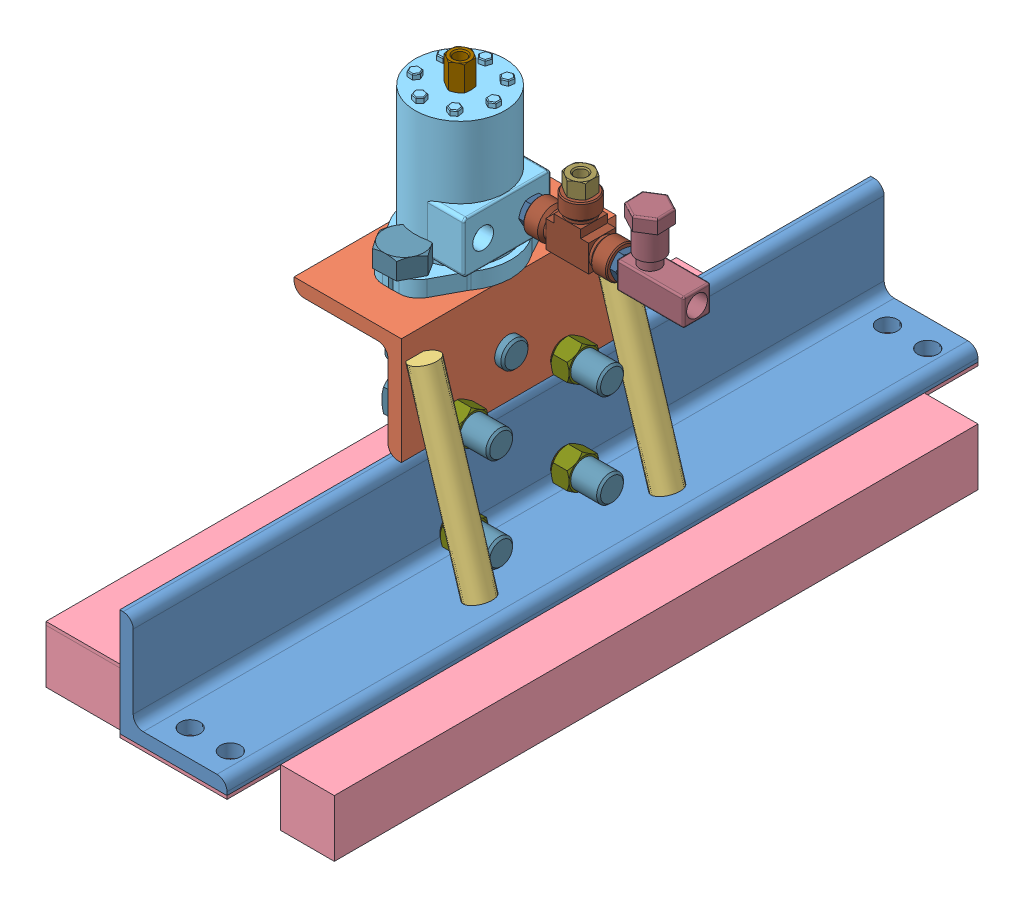
SolidWorks assembly 01-076-00-0, configuration Default. Lengths in mm.
Overall size (295.22 416.18 711.2).
44 component instances, 19 part files, 78 mates.
Components (placement in the parent):
- 01-048-00-0-1: 01-048-00-0 [Default] at (-161.4838 -113.0009 54.5674) size (279.4 257.18 711.2)
  - 01-042-00-0-1: 01-042-00-0 [Default] at origin size (101.6 101.6 711.2)
  - 01-043-00-0-1: 01-043-00-0 [Default] at (12.7 203.2 0) x (-1 0 0) z (0 0 1) size (101.6 101.6 203.2)
  - 01-047-00-0-5: 01-047-00-0 [Default] at (74.1068 15.97 -88.9) x (0.948496 0.291905 -0.123074) z (0.11763 0.036201 0.992397) size (25.4 177.8 25.4)
  - 01-047-00-0-7: 01-047-00-0 [Default] at (74.1066 15.5263 89.0193) x (0.948496 0.291905 -0.123074) z (0.11763 0.036201 0.992397) size (25.4 177.8 25.4)
  - 01-074-00-0-1: 01-074-00-0 [Default] at (0 -3.175 298.45) x (0 0 -1) z (1 0 0) size (711.2 53.98 279.4)
- BMPH50H2KP-1: BMPH50H2KP [Default] at (-194.7832 90.1991 54.5674) x (0 0 -1) z (-1 0 0) size (131.32 192.98 96.77)
- 01-077-00-0-1: 01-077-00-0 [Default] at (-220.4962 -153.8949 79.6504) x (0.999923 0 0.012402) z (-0.012402 0 0.999923) size (177.8 190.5 152.4)
  - 01-044-00-0-1: 01-044-00-0 [Default] at origin size (127 25.4 50.8)
  - 01-045-00-0-1: 01-045-00-0 [Default] at (177.8 0 50.8) x (0 0 -1) z (1 0 0) size (152.4 25.4 50.8)
  - 01-046-00-0-1: 01-046-00-0 [Default] at (25.4 6.35 -25.4) size (25.4 184.15 25.4)
- SS-4-SAE-7_4-1: SS-4-SAE-7_4 [Default] at (-194.7832 215.6751 54.5674) x (0 1 0) z (0 0 1) size (33.53 19.05 22)
- Male Hex Nipple, NPT_SS-8-HN_1_2-1: Male Hex Nipple, NPT_SS-8-HN_1_2 [Default] at (-123.1933 132.8711 31.7074) x (-1 0 0) z (0 0 -1) size (46.74 22.23 25.66)
- SS-8-T_3-1: SS-8-T_3 [Default] at (-63.7954 132.8711 31.7074) x (-1 0 0) z (0 -1 0) size (79.25 30.48 54.86)
- SS-8-RB-4-1: SS-8-RB-4 [Default] at (-103.4194 159.7951 31.7074) x (0 1 0) z (0 0 1) size (27.43 22.23 25.66)
- Male Hex Nipple, NPT_SS-8-HN_1_2-2: Male Hex Nipple, NPT_SS-8-HN_1_2 [Default] at (-36.9095 132.8711 31.7074) x (-1 0 0) z (0 -0.924225 -0.381849) size (46.74 22.23 25.66)
- Control Valve - 0.5NPTF-1: Control Valve - 0.5NPTF [Default] at (6.7404 120.1711 19.0074) x (0 0 1) z (-1 0 0) size (34.87 73.03 63.5)
- hex bolt_ai_2-1: hex bolt_ai_2 [PreviewCfg] at (-194.7832 123.2191 107.7804) x (0 -1 0) z (0.883967 0 0.467549) size (93.98 43.99 38.1)
- flat washer type a wide_ai-1: flat washer type a wide_ai [PreviewCfg] at (-194.7832 77.4991 107.7804) x (0 1 0) z (0 0 1) size (4.19 63.5 63.5)
- hex nut_ai-1: hex nut_ai [PreviewCfg] at (-194.7832 56.4171 107.7804) x (0.996756 0 0.080478) z (0 -1 0) size (28.57 33 16.89)
- hex bolt_ai_2-2: hex bolt_ai_2 [PreviewCfg] at (-194.7832 123.2191 1.3544) x (0 -1 0) z (0.883967 0 0.467549) size (93.98 43.99 38.1)
- flat washer type a wide_ai-2: flat washer type a wide_ai [PreviewCfg] at (-194.7832 77.4991 1.3544) x (0 1 0) z (0 0 1) size (4.19 63.5 63.5)
- hex nut_ai-2: hex nut_ai [PreviewCfg] at (-194.7832 56.4171 1.3544) x (0.996756 0 0.080478) z (0 -1 0) size (28.57 33 16.89)
- 01-078-00-0-1: 01-078-00-0 [Default] at (-161.4838 -68.6017 124.5698) x (0 0 -1) z (0 1 0) size (140 67.2 38)
- 01-078-00-0-2: 01-078-00-0 [Default] at (-161.4838 20.2983 124.5698) x (0 0 -1) z (0 1 0) size (140 67.2 38)
- WASHER 0.375-WIDE-1: WASHER 0.375-WIDE [Default] at (-177.4858 -87.6009 107.0565) size (2.11 25.4 25.4)
- hex bolt_ai_2-3: hex bolt_ai_2 [PreviewCfg] at (-197.374 -87.6009 107.0565) size (93.98 43.99 38.1)
- WASHER 0.375-WIDE-2: WASHER 0.375-WIDE [Default] at (-146.6756 -87.6009 107.0565) size (2.11 25.4 25.4)
- hex nut_ai-3: hex nut_ai [PreviewCfg] at (-146.6756 -87.6009 107.0565) x (0 0 1) z (-1 0 0) size (28.57 33 16.89)
- hex bolt_ai_2-4: hex bolt_ai_2 [PreviewCfg] at (-197.374 -87.6009 2.0783) size (93.98 43.99 38.1)
- WASHER 0.375-WIDE-3: WASHER 0.375-WIDE [Default] at (-146.6756 -87.6009 2.0783) size (2.11 25.4 25.4)
- hex nut_ai-4: hex nut_ai [PreviewCfg] at (-146.6756 -87.6009 2.0783) x (0 0 1) z (-1 0 0) size (28.57 33 16.89)
- WASHER 0.375-WIDE-4: WASHER 0.375-WIDE [Default] at (-177.4858 -87.6009 2.0783) size (2.11 25.4 25.4)
- hex bolt_ai_2-5: hex bolt_ai_2 [PreviewCfg] at (-197.374 1.2991 107.0565) size (93.98 43.99 38.1)
- WASHER 0.375-WIDE-5: WASHER 0.375-WIDE [Default] at (-146.6756 1.2991 107.0565) size (2.11 25.4 25.4)
- hex nut_ai-5: hex nut_ai [PreviewCfg] at (-146.6756 1.2991 107.0565) x (0 0 1) z (-1 0 0) size (28.57 33 16.89)
- WASHER 0.375-WIDE-6: WASHER 0.375-WIDE [Default] at (-177.4858 1.2991 107.0565) size (2.11 25.4 25.4)
- hex bolt_ai_2-6: hex bolt_ai_2 [PreviewCfg] at (-197.374 1.2991 2.0783) size (93.98 43.99 38.1)
- WASHER 0.375-WIDE-7: WASHER 0.375-WIDE [Default] at (-146.6756 1.2991 2.0783) size (2.11 25.4 25.4)
- hex nut_ai-6: hex nut_ai [PreviewCfg] at (-146.6756 1.2991 2.0783) x (0 0 1) z (-1 0 0) size (28.57 33 16.89)
- WASHER 0.375-WIDE-8: WASHER 0.375-WIDE [Default] at (-177.4858 1.2991 2.0783) size (2.11 25.4 25.4)
- 01-085-00-0-1: 01-085-00-0 [Default] at (-194.7832 20.7301 54.5674) x (-0.012402 0 0.999923) z (-0.999923 0 -0.012402) size (44.45 50.8 44.45)
- hex bolt_ai_2-7: hex bolt_ai_2 [PreviewCfg] at (-234.7851 30.2551 54.0712) x (0.999923 0 0.012402) z (0.002836 0.973504 -0.228653) size (93.98 43.99 38.1)
- hex nut_ai-7: hex nut_ai [PreviewCfg] at (-172.5599 30.2551 54.843) x (-0.012135 0.206523 0.978366) z (-0.999923 0 -0.012402) size (28.57 33 16.89)
Mates (geometry in assembly coordinates):
- Coincident3: coincident anti-aligned: plane of 01-048-00-0-1/01-043-00-0-1 through (-250.3838 90.1991 156.1674) normal (0 1 0); plane of BMPH50H2KP-1 through (-194.7832 90.1991 54.5674) normal (0 -1 0)
- Concentric3: concentric anti-aligned: cylinder of BMPH50H2KP-1 through (-194.7832 105.4391 1.3544) axis (0 -1 0) radius 6.731; cylinder of 01-048-00-0-1/01-043-00-0-1 through (-194.7832 211.4325 1.3544) axis (0 1 0) radius 7.9375
- Concentric5: concentric anti-aligned: cylinder of BMPH50H2KP-1 through (-194.7832 36.6051 54.5674) axis (0 1 0) radius 12.7; cylinder of 01-077-00-0-1/01-044-00-0-1 through (-194.7832 -128.4939 54.5674) axis (0 -1 0) radius 12.7
- Concentric7: concentric anti-aligned: cylinder of BMPH50H2KP-1 through (-194.7832 36.6051 54.5674) axis (0 1 0) radius 12.7; cylinder of 01-077-00-0-1/01-046-00-0-1 through (-194.7832 36.6051 54.5674) axis (0 -1 0) radius 12.7
- Concentric8: concentric aligned: cylinder of SS-4-SAE-7_4-1 through (-194.7832 219.1168 54.5674) axis (0 1 0) radius 5.5563; cylinder of BMPH50H2KP-1 through (-194.7832 224.8191 54.5674) axis (0 1 0) radius 4.9606
- Coincident4: coincident anti-aligned: plane of BMPH50H2KP-1 through (-194.7832 224.8191 54.5674) normal (0 1 0); plane of SS-4-SAE-7_4-1 through (-194.7832 224.8191 59.3299) normal (0 -1 0)
- Coincident5: coincident anti-aligned: plane of BMPH50H2KP-1 through (-150.0792 108.6141 13.2924) normal (1 0 0); circle of Male Hex Nipple, NPT_SS-8-HN_1_2-1
- Concentric10: concentric aligned: cone of BMPH50H2KP-1 through (-150.0792 132.8711 31.7074) axis (-1 0 0); cone of Male Hex Nipple, NPT_SS-8-HN_1_2-1 through (-156.3733 132.8711 31.7074) axis (-1 0 0)
- Coincident6: coincident aligned: circle of Male Hex Nipple, NPT_SS-8-HN_1_2-1; plane of SS-8-T_3-1 through (-143.0434 132.8711 31.7074) normal (-1 0 0)
- Concentric11: concentric anti-aligned: cylinder of Male Hex Nipple, NPT_SS-8-HN_1_2-1 through (-136.7493 132.8711 31.7074) axis (-1 0 0) radius 10.668; cylinder of SS-8-T_3-1 through (-143.0434 132.8711 31.7074) axis (1 0 0) radius 15.24
- Parallel1: parallel anti-aligned: plane of SS-8-T_3-1 through (-123.7394 120.1711 19.0074) normal (0 0 -1); plane of assembly through (0 0 0) normal (0 0 1)
- Concentric12: concentric aligned: cone of SS-8-T_3-1 through (-103.4194 158.9239 31.7074) axis (0 -1 0); cone of SS-8-RB-4-1 through (-103.4194 172.4951 31.7074) axis (0 -1 0)
- Coincident8: coincident anti-aligned: plane of SS-8-T_3-1 through (-103.4194 172.4951 31.7074) normal (0 1 0); circle of SS-8-RB-4-1
- Concentric13: concentric aligned: cone of SS-8-T_3-1 through (-77.3666 132.8711 31.7074) axis (-1 0 0); cone of Male Hex Nipple, NPT_SS-8-HN_1_2-2 through (-70.0895 132.8711 31.7074) axis (-1 0 0)
- Coincident9: coincident anti-aligned: plane of SS-8-T_3-1 through (-63.7954 132.8711 31.7074) normal (1 0 0); circle of Male Hex Nipple, NPT_SS-8-HN_1_2-2
- Concentric14: concentric aligned: cone of Male Hex Nipple, NPT_SS-8-HN_1_2-2 through (-50.4655 132.8711 31.7074) axis (1 0 0); cone of Control Valve - 0.5NPTF-1 through (-56.7596 132.8711 31.7074) axis (1 0 0)
- Coincident10: coincident aligned: circle of Male Hex Nipple, NPT_SS-8-HN_1_2-2; plane of Control Valve - 0.5NPTF-1 through (-56.7596 145.5711 19.0074) normal (-1 0 0)
- Concentric15: concentric anti-aligned: cylinder of 01-048-00-0-1/01-043-00-0-1 through (-194.7832 211.4325 107.7804) axis (0 1 0) radius 7.9375; cylinder of BMPH50H2KP-1 through (-194.7832 105.4391 107.7804) axis (0 -1 0) radius 6.731
- Coincident12: coincident aligned: plane of SS-8-T_3-1 through (-123.7394 120.1711 19.0074) normal (0 0 -1); plane of Control Valve - 0.5NPTF-1 through (-56.7596 120.1711 19.0074) normal (0 0 -1)
- Coincident13: coincident anti-aligned: plane of BMPH50H2KP-1 through (-194.7832 105.4391 54.5674) normal (0 1 0); plane of hex bolt_ai_2-1 through (-184.4985 105.4391 88.3357) normal (0 -1 0)
- Concentric16: concentric anti-aligned: cylinder of BMPH50H2KP-1 through (-194.7832 105.4391 107.7804) axis (0 -1 0) radius 6.731; cylinder of hex bolt_ai_2-1 through (-194.7832 123.2191 107.7804) axis (0 1 0) radius 12.7
- Concentric171: concentric anti-aligned: cylinder of hex bolt_ai_2-1 through (-194.7832 123.2191 107.7804) axis (0 1 0) radius 12.7; cylinder of hex nut_ai-1 through (-194.7832 81.4546 107.7804) axis (0 -1 0) radius 9.525
- Coincident141: coincident anti-aligned: plane of flat washer type a wide_ai-1 through (-226.5332 73.3081 107.7804) normal (0 -1 0); plane of hex nut_ai-1 through (-196.1109 73.3081 124.2246) normal (0 1 0)
- Coincident15: coincident anti-aligned: plane of 01-048-00-0-1/01-043-00-0-1 through (-171.0088 77.4991 156.1674) normal (0 -1 0); plane of flat washer type a wide_ai-1 through (-208.2706 77.4991 107.7804) normal (0 1 0)
- Concentric18: concentric anti-aligned: cylinder of hex bolt_ai_2-2 through (-194.7832 123.2191 1.3544) axis (0 1 0) radius 12.7; cylinder of hex nut_ai-2 through (-194.7832 81.4546 1.3544) axis (0 -1 0) radius 9.525
- Coincident16: coincident anti-aligned: plane of flat washer type a wide_ai-2 through (-226.5332 73.3081 1.3544) normal (0 -1 0); plane of hex nut_ai-2 through (-196.1109 73.3081 17.7986) normal (0 1 0)
- Coincident17: coincident anti-aligned: plane of BMPH50H2KP-1 through (-194.7832 105.4391 54.5674) normal (0 1 0); plane of hex bolt_ai_2-2 through (-184.4985 105.4391 -18.0903) normal (0 -1 0)
- Concentric19: concentric anti-aligned: cylinder of BMPH50H2KP-1 through (-194.7832 105.4391 1.3544) axis (0 -1 0) radius 6.731; cylinder of hex bolt_ai_2-2 through (-194.7832 123.2191 1.3544) axis (0 1 0) radius 12.7
- Coincident18: coincident anti-aligned: plane of 01-048-00-0-1/01-043-00-0-1 through (-171.0088 77.4991 156.1674) normal (0 -1 0); plane of flat washer type a wide_ai-2 through (-208.2706 77.4991 1.3544) normal (0 1 0)
- Concentric20: concentric aligned: circle of 01-048-00-0-1/01-043-00-0-1; cylinder of flat washer type a wide_ai-2 through (-194.7832 42.5741 1.3544) axis (0 -1 0) radius 13.4874
- Coincident19: coincident anti-aligned: plane of 01-048-00-0-1/01-042-00-0-1 through (-161.4838 -113.0009 410.1674) normal (-1 0 0); plane of 01-078-00-0-1 through (-161.4838 -106.6001 124.5698) normal (1 0 0)
- Perpendicular1: perpendicular: plane of 01-078-00-0-1 through (-177.4858 -106.6001 124.5698) normal (0 -1 0); plane of assembly through (0 0 54.5674) normal (0 0 1)
- Coincident22: coincident: moEndPointRef_w of 01-078-00-0-1; plane of assembly
- Distance4: distance = 25.4 mm anti-aligned: moEndPointRef_w of 01-078-00-0-1; plane of 01-048-00-0-1/01-042-00-0-1 through (-59.8838 -113.0009 410.1674) normal (0 -1 0)
- Coincident23: coincident anti-aligned: plane of 01-048-00-0-1/01-043-00-0-1 through (-161.4838 -1.881 156.1674) normal (-1 0 0); plane of 01-078-00-0-2 through (-161.4838 -17.7001 124.5698) normal (1 0 0)
- Perpendicular2: perpendicular: plane of 01-078-00-0-2 through (-177.4858 -17.7001 124.5698) normal (0 -1 0); plane of assembly through (0 0 54.5674) normal (0 0 1)
- Coincident24: coincident: moEndPointRef_w of 01-078-00-0-2; plane of assembly
- Distance5: distance = 12.7 mm anti-aligned: moEndPointRef_w of 01-078-00-0-2; plane of 01-048-00-0-1/01-043-00-0-1 through (-148.7838 -11.4009 156.1674) normal (0 -1 0)
- Coincident25: coincident anti-aligned: plane of 01-078-00-0-1 through (-177.4858 -106.6001 124.5698) normal (-1 0 0); plane of WASHER 0.375-WIDE-1 through (-177.4858 -82.0383 107.0565) normal (1 0 0)
- Concentric22: concentric aligned: cylinder of 01-048-00-0-1/01-042-00-0-1 through (-59.8828 -87.6009 107.0565) axis (-1 0 0) radius 6.35; cylinder of WASHER 0.375-WIDE-1 through (-212.4108 -87.6009 107.0565) axis (-1 0 0) radius 5.5626
- Concentric231: concentric aligned: cylinder of WASHER 0.375-WIDE-1 through (-212.4108 -87.6009 107.0565) axis (-1 0 0) radius 12.7; cylinder of hex bolt_ai_2-3 through (-197.374 -87.6009 107.0565) axis (-1 0 0) radius 12.7
- Coincident261: coincident anti-aligned: plane of WASHER 0.375-WIDE-1 through (-179.594 -74.9009 107.0565) normal (-1 0 0); plane of hex bolt_ai_2-3 through (-179.594 -65.6039 107.0565) normal (1 0 0)
- Coincident27: coincident anti-aligned: plane of 01-048-00-0-1/01-042-00-0-1 through (-148.7838 -20.9208 410.1674) normal (1 0 0); plane of WASHER 0.375-WIDE-2 through (-148.7838 -74.9009 107.0565) normal (-1 0 0)
- Concentric24: concentric aligned: cylinder of hex bolt_ai_2-3 through (-197.374 -87.6009 107.0565) axis (-1 0 0) radius 12.7; cylinder of WASHER 0.375-WIDE-2 through (-181.6006 -87.6009 107.0565) axis (-1 0 0) radius 5.5626
- Coincident28: coincident anti-aligned: plane of WASHER 0.375-WIDE-2 through (-146.6756 -82.0383 107.0565) normal (1 0 0); plane of hex nut_ai-3 through (-146.6756 -71.1031 107.0565) normal (-1 0 0)
- Concentric25: concentric aligned: cylinder of WASHER 0.375-WIDE-2 through (-181.6006 -87.6009 107.0565) axis (-1 0 0) radius 12.7; cylinder of hex nut_ai-3 through (-129.7846 -87.6009 107.0565) axis (-1 0 0) radius 8.3337
- Concentric26: concentric aligned: cylinder of hex bolt_ai_2-4 through (-197.374 -87.6009 2.0783) axis (-1 0 0) radius 12.7; cylinder of WASHER 0.375-WIDE-4 through (-212.4108 -87.6009 2.0783) axis (-1 0 0) radius 12.7
- Coincident29: coincident anti-aligned: plane of hex bolt_ai_2-4 through (-179.594 -65.6039 2.0783) normal (1 0 0); plane of WASHER 0.375-WIDE-4 through (-179.594 -74.9009 2.0783) normal (-1 0 0)
- Concentric27: concentric aligned: cylinder of hex bolt_ai_2-4 through (-197.374 -87.6009 2.0783) axis (-1 0 0) radius 12.7; cylinder of WASHER 0.375-WIDE-3 through (-181.6006 -87.6009 2.0783) axis (-1 0 0) radius 5.5626
- Coincident30: coincident anti-aligned: plane of WASHER 0.375-WIDE-3 through (-146.6756 -82.0383 2.0783) normal (1 0 0); plane of hex nut_ai-4 through (-146.6756 -71.1031 2.0783) normal (-1 0 0)
- Concentric28: concentric aligned: cylinder of WASHER 0.375-WIDE-3 through (-181.6006 -87.6009 2.0783) axis (-1 0 0) radius 12.7; cylinder of hex nut_ai-4 through (-129.7846 -87.6009 2.0783) axis (-1 0 0) radius 8.3337
- Coincident31: coincident anti-aligned: plane of 01-078-00-0-1 through (-177.4858 -106.6001 124.5698) normal (-1 0 0); plane of WASHER 0.375-WIDE-4 through (-177.4858 -82.0383 2.0783) normal (1 0 0)
- Concentric29: concentric aligned: cylinder of 01-048-00-0-1/01-042-00-0-1 through (-59.8828 -87.6009 2.0783) axis (-1 0 0) radius 6.35; cylinder of WASHER 0.375-WIDE-4 through (-212.4108 -87.6009 2.0783) axis (-1 0 0) radius 5.5626
- Coincident32: coincident anti-aligned: plane of 01-048-00-0-1/01-042-00-0-1 through (-148.7838 -20.9208 410.1674) normal (1 0 0); plane of WASHER 0.375-WIDE-3 through (-148.7838 -74.9009 2.0783) normal (-1 0 0)
- Concentric30: concentric aligned: cylinder of hex bolt_ai_2-5 through (-197.374 1.2991 107.0565) axis (-1 0 0) radius 12.7; cylinder of WASHER 0.375-WIDE-6 through (-212.4108 1.2991 107.0565) axis (-1 0 0) radius 12.7
- Coincident33: coincident anti-aligned: plane of hex bolt_ai_2-5 through (-179.594 23.2961 107.0565) normal (1 0 0); plane of WASHER 0.375-WIDE-6 through (-179.594 13.9991 107.0565) normal (-1 0 0)
- Concentric31: concentric aligned: cylinder of hex bolt_ai_2-5 through (-197.374 1.2991 107.0565) axis (-1 0 0) radius 12.7; cylinder of WASHER 0.375-WIDE-5 through (-181.6006 1.2991 107.0565) axis (-1 0 0) radius 5.5626
- Coincident34: coincident anti-aligned: plane of WASHER 0.375-WIDE-5 through (-146.6756 6.8617 107.0565) normal (1 0 0); plane of hex nut_ai-5 through (-146.6756 17.7969 107.0565) normal (-1 0 0)
- Concentric32: concentric aligned: cylinder of WASHER 0.375-WIDE-5 through (-181.6006 1.2991 107.0565) axis (-1 0 0) radius 12.7; cylinder of hex nut_ai-5 through (-129.7846 1.2991 107.0565) axis (-1 0 0) radius 8.3337
- Coincident35: coincident anti-aligned: plane of 01-078-00-0-2 through (-177.4858 -17.7001 124.5698) normal (-1 0 0); plane of WASHER 0.375-WIDE-6 through (-177.4858 6.8617 107.0565) normal (1 0 0)
- Coincident36: coincident anti-aligned: plane of 01-048-00-0-1/01-042-00-0-1 through (-148.7838 -20.9208 410.1674) normal (1 0 0); plane of WASHER 0.375-WIDE-5 through (-148.7838 13.9991 107.0565) normal (-1 0 0)
- Concentric33: concentric aligned: cylinder of 01-048-00-0-1/01-043-00-0-1 through (-148.7828 1.2991 107.0565) axis (-1 0 0) radius 6.35; cylinder of WASHER 0.375-WIDE-6 through (-212.4108 1.2991 107.0565) axis (-1 0 0) radius 5.5626
- Concentric34: concentric aligned: cylinder of hex bolt_ai_2-6 through (-197.374 1.2991 2.0783) axis (-1 0 0) radius 12.7; cylinder of WASHER 0.375-WIDE-8 through (-212.4108 1.2991 2.0783) axis (-1 0 0) radius 12.7
- Coincident37: coincident anti-aligned: plane of hex bolt_ai_2-6 through (-179.594 23.2961 2.0783) normal (1 0 0); plane of WASHER 0.375-WIDE-8 through (-179.594 13.9991 2.0783) normal (-1 0 0)
- Concentric35: concentric aligned: cylinder of hex bolt_ai_2-6 through (-197.374 1.2991 2.0783) axis (-1 0 0) radius 12.7; cylinder of WASHER 0.375-WIDE-7 through (-181.6006 1.2991 2.0783) axis (-1 0 0) radius 5.5626
- Coincident38: coincident anti-aligned: plane of WASHER 0.375-WIDE-7 through (-146.6756 6.8617 2.0783) normal (1 0 0); plane of hex nut_ai-6 through (-146.6756 17.7969 2.0783) normal (-1 0 0)
- Concentric36: concentric aligned: cylinder of WASHER 0.375-WIDE-7 through (-181.6006 1.2991 2.0783) axis (-1 0 0) radius 12.7; cylinder of hex nut_ai-6 through (-129.7846 1.2991 2.0783) axis (-1 0 0) radius 8.3337
- Coincident39: coincident anti-aligned: plane of 01-078-00-0-2 through (-177.4858 -17.7001 124.5698) normal (-1 0 0); plane of WASHER 0.375-WIDE-8 through (-177.4858 6.8617 2.0783) normal (1 0 0)
- Coincident40: coincident anti-aligned: plane of 01-048-00-0-1/01-042-00-0-1 through (-148.7838 -20.9208 410.1674) normal (1 0 0); plane of WASHER 0.375-WIDE-7 through (-148.7838 13.9991 2.0783) normal (-1 0 0)
- Concentric37: concentric aligned: cylinder of 01-048-00-0-1/01-043-00-0-1 through (-148.7828 1.2991 2.0783) axis (-1 0 0) radius 6.35; cylinder of WASHER 0.375-WIDE-8 through (-212.4108 1.2991 2.0783) axis (-1 0 0) radius 5.5626
- Concentric38: concentric anti-aligned: cylinder of hex bolt_ai_2-1 through (-194.7832 123.2191 107.7804) axis (0 1 0) radius 12.7; cylinder of flat washer type a wide_ai-1 through (-194.7832 42.5741 107.7804) axis (0 -1 0) radius 13.4874
- Concentric232: concentric anti-aligned: cylinder of 01-077-00-0-1/01-046-00-0-1 through (-207.4822 30.2551 54.4099) axis (0.999923 0 0.012402) radius 3.175; cylinder of 01-085-00-0-1 through (-172.5599 30.2551 54.843) axis (-0.999923 0 -0.012402) radius 3.175
- Concentric233: concentric aligned: cylinder of 01-077-00-0-1/01-046-00-0-1 through (-194.7832 36.6051 54.5674) axis (0 -1 0) radius 12.7; cylinder of 01-085-00-0-1 through (-194.7832 71.5301 54.5674) axis (0 -1 0) radius 22.225
- Coincident262: coincident anti-aligned: plane of BMPH50H2KP-1 through (-194.7832 36.6051 54.5674) normal (0 -1 0); plane of 01-077-00-0-1/01-046-00-0-1 through (-194.7832 36.6051 54.5674) normal (0 1 0)
- Concentric234: concentric aligned: cylinder of 01-085-00-0-1 through (-172.5599 30.2551 54.843) axis (-0.999923 0 -0.012402) radius 3.175; cylinder of hex bolt_ai_2-7 through (-234.7851 30.2551 54.0712) axis (-0.999923 0 -0.012402) radius 12.7
- Tangent1: tangent anti-aligned: cylinder of 01-085-00-0-1 through (-194.7832 71.5301 54.5674) axis (0 -1 0) radius 22.225; plane of hex bolt_ai_2-7 through (-216.7409 25.225 32.8792) normal (0.999923 0 0.012402)
- Concentric235: concentric anti-aligned: cylinder of hex bolt_ai_2-7 through (-234.7851 30.2551 54.0712) axis (-0.999923 0 -0.012402) radius 12.7; circle of hex nut_ai-7
- Tangent3: tangent anti-aligned: cylinder of 01-085-00-0-1 through (-194.7832 71.5301 54.5674) axis (0 -1 0) radius 22.225; plane of hex nut_ai-7 through (-172.5176 46.3972 51.4361) normal (-0.999923 0 -0.012402)
